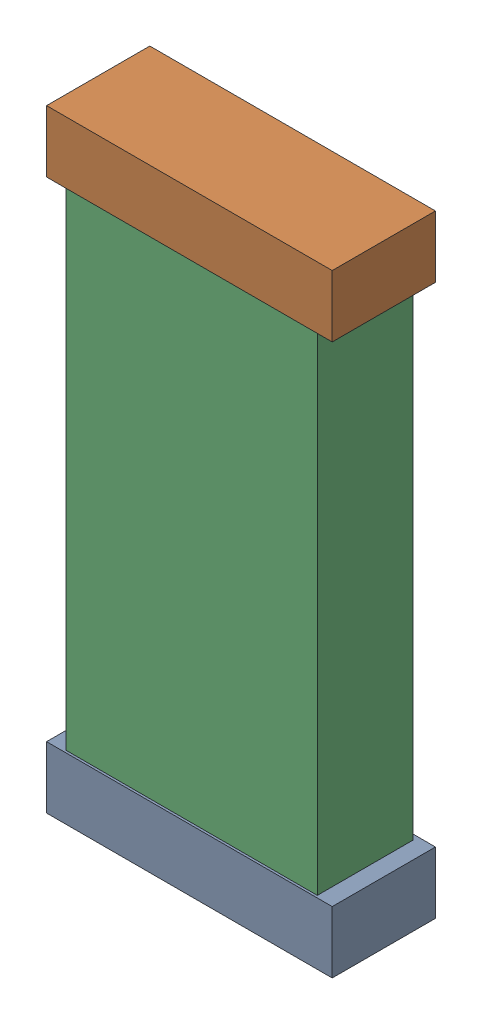
SolidWorks assembly C10, configuration Default. Lengths in mm.
Overall size (1.27 2.72 0.46).
6 component instances, 2 part files, 0 mates.
Components (placement in the parent):
- 804388560_2-1: 804388560_2 [Default] at (40.4066 18.7112 0.001) size (1.27 0.28 0.46)
  - Extruded (23)-1: Extruded (23) [Default] at origin size (1.27 0.28 0.46)
- 804388560_3-1: 804388560_3 [Default] at (40.4066 21.1601 0.001) size (1.27 0.28 0.46)
  - Extruded (23)-1: Extruded (23) [Default] at origin size (1.27 0.28 0.46)
- 804388688_1-1: 804388688_1 [Default] at (40.4066 19.8796 0.025) size (1.12 2.29 0.42)
  - Extruded (24)-1: Extruded (24) [Default] at origin size (1.12 2.29 0.42)
